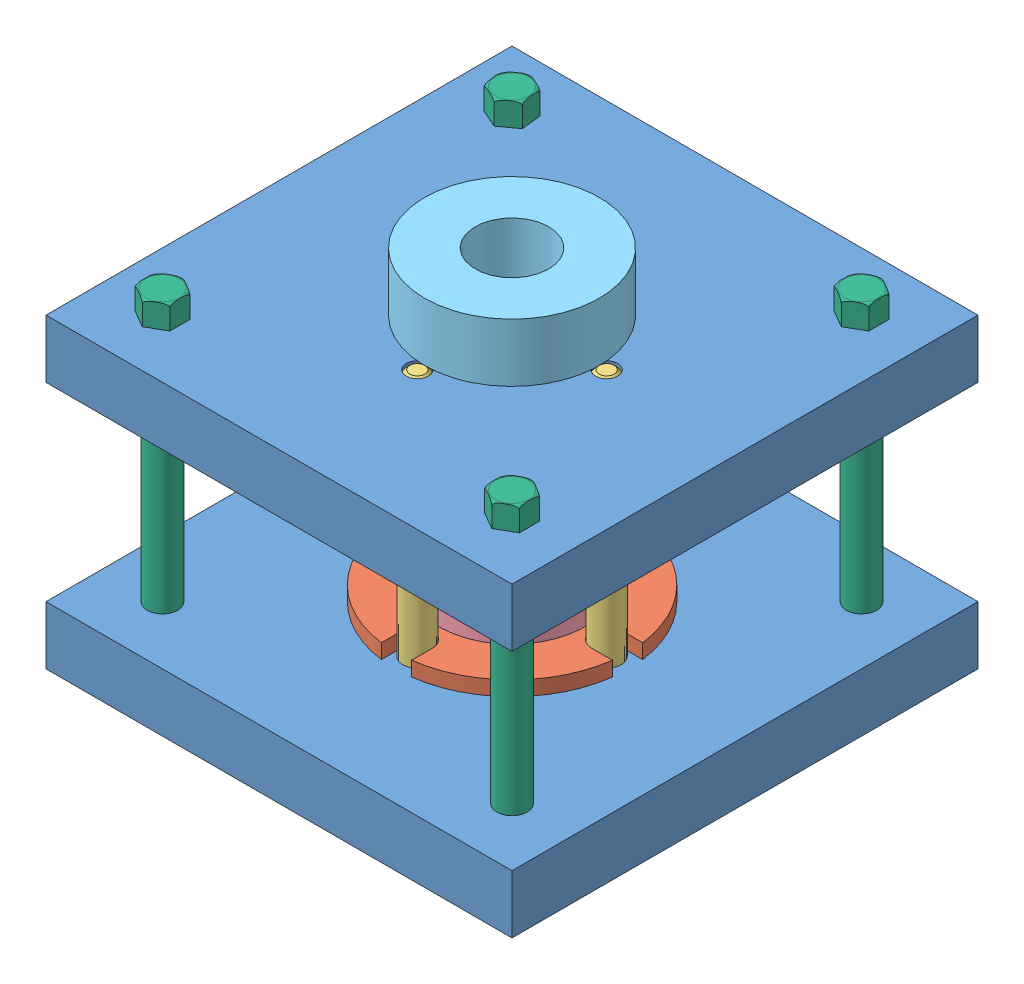
SolidWorks assembly Assem1, configuration Default. Lengths in mm.
Overall size (101.6 88.9 101.6).
17 component instances, 7 part files, 34 mates.
Components (placement in the parent):
- end plate-1: end plate [Default] at (38.6541 41.0949 81.3897) size (101.6 12.7 101.6)
- disk-1: disk [Default] at (38.6541 53.7949 81.377) size (50.37 3.17 50.37)
- support pin-1: support pin [Default] at (38.6541 41.0949 102.0272) x (0.77938 0 -0.626551) z (0.626551 0 0.77938) size (6.35 66.8 6.35)
- support pin-5: support pin [Default] at (59.2916 41.0949 81.3897) size (6.35 66.8 6.35)
- support pin-6: support pin [Default] at (18.0166 41.0949 81.3897) size (6.35 66.8 6.35)
- support pin-7: support pin [Default] at (38.6541 41.0949 60.7522) size (6.35 66.8 6.35)
- spacer-1: spacer [Default] at (38.6541 41.0949 81.3897) x (0.999716 0 0.023812) z (-0.023812 0 0.999716) size (31.75 34.92 31.75)
- centre pin-1: centre pin [Default] at (38.6541 107.8969 81.3897) x (0.930666 0 -0.365869) z (0.365869 0 0.930666) size (38.1 76.2 38.1)
- end plate-2: end plate [Default] at (38.6541 95.1969 81.3897) size (101.6 12.7 101.6)
- bolt-1: bolt [Default] at (76.7541 107.8969 119.4897) size (8.01 81.55 9.19)
- bolt-2: bolt [Default] at (0.5541 107.8969 119.4897) size (8.01 81.55 9.19)
- bolt-3: bolt [Default] at (0.5541 107.8969 43.2897) x (0.589865 0 0.807502) z (-0.807502 0 0.589865) size (8.01 81.55 9.19)
- bolt-4: bolt [Default] at (76.7541 107.8969 43.2897) size (8.01 81.55 9.19)
- nut-2: nut [Default] at (76.7541 36.0149 119.4897) size (10.4 5.26 9.03)
- nut-4: nut [Default] at (0.5541 36.0149 119.4897) x (0.983742 0 -0.179585) z (0.179585 0 0.983742) size (10.4 5.26 9.03)
- nut-5: nut [Default] at (0.5541 36.0149 43.2897) x (-0.689104 0 -0.724663) z (0.724663 0 -0.689104) size (10.4 5.26 9.03)
- nut-6: nut [Default] at (76.7541 36.0149 43.2897) x (0.614363 0 -0.789023) z (0.789023 0 0.614363) size (10.4 5.26 9.03)
Mates (geometry in assembly coordinates):
- Concentric1: concentric: circle of end plate-1; circle of disk-1
- Concentric3: concentric: cylinder of end plate-1 through (38.6541 53.7949 102.0272) axis (0 -1 0) radius 2.413; cylinder of disk-1 through (38.6541 56.9699 102.0272) axis (0 -1 0) radius 3.302
- Coincident1: coincident anti-aligned: plane of end plate-1 through (38.6541 53.7949 81.3897) normal (0 1 0); plane of disk-1 through (59.3043 53.7949 81.377) normal (0 -1 0)
- Concentric8: concentric anti-aligned: circle of end plate-1; cylinder of support pin-1 through (38.6541 53.7949 102.0272) axis (0 -1 0) radius 2.413
- Coincident6: coincident anti-aligned: circle of end plate-1; cylinder of support pin-5 through (59.2916 53.7949 81.3897) axis (0 -1 0) radius 2.413
- Concentric9: concentric aligned: cylinder of end plate-1 through (38.6541 53.7949 60.7522) axis (0 -1 0) radius 2.413; cylinder of support pin-7 through (38.6541 53.7949 60.7522) axis (0 -1 0) radius 2.413
- Coincident7: coincident anti-aligned: circle of end plate-1; cylinder of support pin-6 through (18.0166 53.7949 81.3897) axis (0 -1 0) radius 2.413
- Coincident8: coincident aligned: plane of end plate-1 through (38.6541 53.7949 81.3897) normal (0 1 0); circle of support pin-6
- Coincident9: coincident aligned: plane of end plate-1 through (38.6541 53.7949 81.3897) normal (0 1 0); circle of support pin-1
- Coincident10: coincident aligned: plane of end plate-1 through (38.6541 53.7949 81.3897) normal (0 1 0); circle of support pin-5
- Coincident11: coincident aligned: plane of end plate-1 through (38.6541 53.7949 81.3897) normal (0 1 0); circle of support pin-7
- Concentric10: concentric aligned: cylinder of end plate-1 through (38.6541 53.7949 81.3897) axis (0 -1 0) radius 12.7; cylinder of spacer-1 through (38.6541 76.0199 81.3897) axis (0 -1 0) radius 15.875
- Coincident12: coincident anti-aligned: circle of end plate-1; plane of spacer-1 through (38.6541 41.0949 81.3897) normal (0 -1 0)
- Concentric11: concentric anti-aligned: cylinder of spacer-1 through (38.6541 76.0199 81.3897) axis (0 -1 0) radius 12.7; cylinder of centre pin-1 through (38.6541 44.3969 81.3897) axis (0 1 0) radius 12.7
- Concentric12: concentric aligned: circle of end plate-1; circle of end plate-2
- Concentric13: concentric aligned: circle of centre pin-1; circle of end plate-2
- Coincident14: coincident aligned: plane of support pin-5 through (59.2916 107.8969 81.3897) normal (0 1 0); plane of end plate-2 through (38.6541 107.8969 81.3897) normal (0 1 0)
- Coincident15: coincident aligned: circle of centre pin-1; plane of end plate-2 through (38.6541 107.8969 81.3897) normal (0 1 0)
- Concentric14: concentric aligned: circle of end plate-2; cylinder of bolt-1 through (76.7541 31.6969 119.4897) axis (0 1 0) radius 3.302
- Coincident16: coincident aligned: circle of end plate-2; cylinder of bolt-2 through (0.5541 31.6969 119.4897) axis (0 1 0) radius 3.302
- Coincident17: coincident aligned: circle of end plate-2; cylinder of bolt-3 through (0.5541 31.6969 43.2897) axis (0 1 0) radius 3.302
- Coincident18: coincident aligned: circle of end plate-2; cylinder of bolt-4 through (76.7541 31.6969 43.2897) axis (0 1 0) radius 3.302
- Coincident19: coincident: plane of end plate-2 through (38.6541 107.8969 81.3897) normal (0 1 0); line of bolt-1 through (80.5641 107.8969 121.6894) axis (0 0 -1)
- Coincident20: coincident: plane of end plate-2 through (38.6541 107.8969 81.3897) normal (0 1 0); line of bolt-4 through (80.5641 107.8969 45.4894) axis (0 0 -1)
- Coincident21: coincident: plane of end plate-2 through (38.6541 107.8969 81.3897) normal (0 1 0); line of bolt-3 through (1.0252 107.8969 47.6638) axis (0.807502 0 -0.589865)
- Coincident22: coincident: plane of end plate-2 through (38.6541 107.8969 81.3897) normal (0 1 0); line of bolt-2 through (4.3641 107.8969 121.6894) axis (0 0 -1)
- Concentric15: concentric anti-aligned: circle of bolt-2; circle of nut-4
- Concentric16: concentric anti-aligned: cylinder of bolt-1 through (76.7541 31.6969 119.4897) axis (0 1 0) radius 3.302; cylinder of nut-2 through (76.7541 41.0949 119.4897) axis (0 -1 0) radius 3.302
- Coincident27: coincident: plane of end plate-1 through (38.6541 41.0949 81.3897) normal (0 -1 0); line of nut-2 through (73.7443 41.0949 115.8129) axis (-0.5 0 0.866025)
- Coincident30: coincident: plane of end plate-1 through (38.6541 41.0949 81.3897) normal (0 -1 0); line of nut-4 through (-3.0671 41.0949 116.4131) axis (-0.336346 0 0.941738)
- Concentric18: concentric anti-aligned: cylinder of bolt-4 through (76.7541 31.6969 43.2897) axis (0 1 0) radius 3.302; cylinder of nut-6 through (76.7541 41.0949 43.2897) axis (0 -1 0) radius 3.302
- Coincident32: coincident aligned: cylinder of bolt-3 through (0.5541 31.6969 43.2897) axis (0 1 0) radius 3.302; circle of nut-5
- Coincident33: coincident: plane of end plate-1 through (38.6541 41.0949 81.3897) normal (0 -1 0); line of nut-6 through (74.2786 41.0949 39.2338) axis (-0.614363 0 0.789023)
- Coincident34: coincident: plane of end plate-1 through (38.6541 41.0949 81.3897) normal (0 -1 0); line of nut-5 through (-3.2339 41.0949 40.421) axis (-0.283024 0 0.959113)
